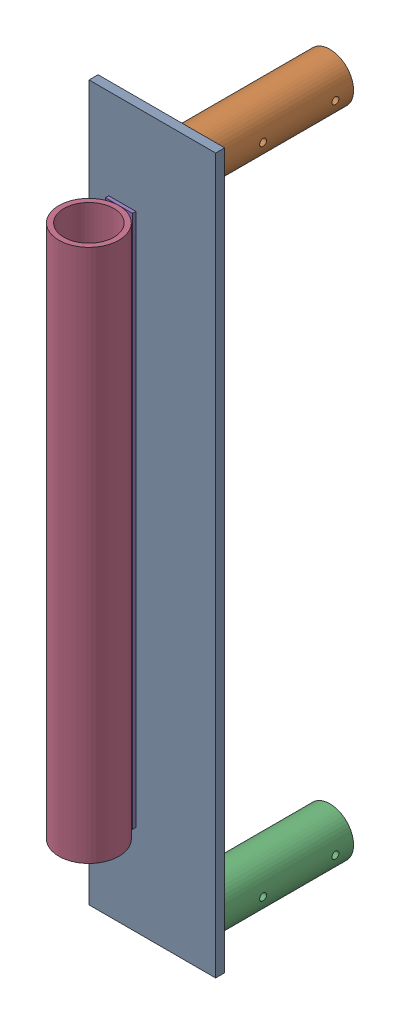
SolidWorks assembly FE-00018_ASM, configuration Default. Lengths in mm.
Overall size (88.9 501.65 152.5).
5 component instances, 4 part files, 0 mates.
Components (placement in the parent):
- FE-00018-03-1: FE-00018-03 [Default] at origin size (88.9 501.65 6.35)
- FE-00018-02-1: FE-00018-02 [Default] at (61.1187 480.2188 -101.6) size (33.4 33.4 101.6)
- FE-00018-02-2: FE-00018-02 [Default] at (61.1124 21.4312 -101.6) size (33.4 33.4 101.6)
- FE-00018-01-1: FE-00018-01 [Default] at (23.368 63.5 29.8196) x (1 0 0) z (0 1 0) size (42.16 42.16 374.65)
- FE-00018-04-1: FE-00018-04 [Default] at (23.368 250.825 6.35) size (19.05 374.65 2.38)
